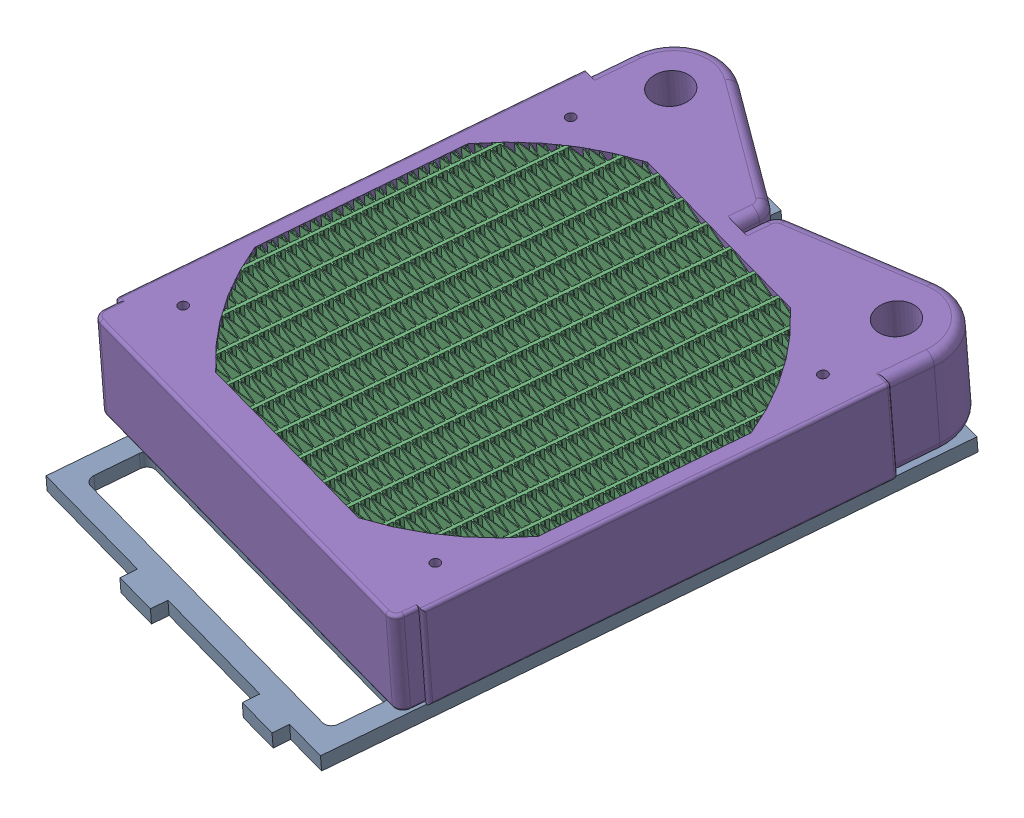
SolidWorks assembly Radiator Panel, configuration Default. Lengths in mm.
Overall size (161.44 74.04 205.59).
6 component instances, 3 part files, 12 mates.
Components (placement in the parent):
- Radiator Panel-1: Radiator Panel [Default] at (-37.0498 33.3786 -16.5806) x (-0.974635 0.090692 -0.204603) z (-0.214715 -0.121053 0.969146) size (114.3 4.76 187.33)
- MCR120-1: MCR120 [Default] at (-50.8395 45.9487 54.6789) x (0.974635 -0.090692 0.204603) z (-0.214715 -0.121053 0.969146) size (128 30.16 162)
- 0.25in Spacer-1: 0.25in Spacer [Default] at (2.846 22.262 45.0413) x (0.997996 -0.063126 -0.004364) z (-0.004364 -0.137455 0.990498) size (6.35 6.35 6.35)
- 0.25in Spacer-2: 0.25in Spacer [Default] at (-99.4907 31.7846 23.5579) x (0.997996 -0.063126 -0.004364) z (-0.004364 -0.137455 0.990498) size (6.35 6.35 6.35)
- 0.25in Spacer-3: 0.25in Spacer [Default] at (-76.9455 44.4952 -78.2024) x (0.997996 -0.063126 -0.004364) z (-0.004364 -0.137455 0.990498) size (6.35 6.35 6.35)
- 0.25in Spacer-4: 0.25in Spacer [Default] at (25.3911 34.9725 -56.719) x (0.997996 -0.063126 -0.004364) z (-0.004364 -0.137455 0.990498) size (6.35 6.35 6.35)
Mates (geometry in assembly coordinates):
- Concentric1: concentric aligned: circle of Radiator Panel-1; circle of MCR120-1
- Concentric2: concentric anti-aligned: circle of Radiator Panel-1; circle of MCR120-1
- Concentric3: concentric aligned: circle of Radiator Panel-1; circle of MCR120-1
- Concentric4: concentric aligned: circle of Radiator Panel-1; circle of 0.25in Spacer-1
- Coincident2: coincident anti-aligned: plane of Radiator Panel-1 through (-0.4376 17.4339 81.2696) normal (0.063126 0.988494 0.137455); plane of 0.25in Spacer-1 through (2.846 22.262 45.0413) normal (-0.063126 -0.988494 -0.137455)
- Concentric5: concentric aligned: circle of Radiator Panel-1; circle of 0.25in Spacer-2
- Coincident3: coincident anti-aligned: plane of Radiator Panel-1 through (-0.4376 17.4339 81.2696) normal (0.063126 0.988494 0.137455); plane of 0.25in Spacer-2 through (-99.4907 31.7846 23.5579) normal (-0.063126 -0.988494 -0.137455)
- Concentric6: concentric aligned: circle of Radiator Panel-1; circle of 0.25in Spacer-4
- Coincident4: coincident anti-aligned: plane of Radiator Panel-1 through (-0.4376 17.4339 81.2696) normal (0.063126 0.988494 0.137455); plane of 0.25in Spacer-4 through (25.3911 34.9725 -56.719) normal (-0.063126 -0.988494 -0.137455)
- Concentric7: concentric aligned: circle of Radiator Panel-1; circle of 0.25in Spacer-3
- Coincident5: coincident anti-aligned: plane of Radiator Panel-1 through (-0.4376 17.4339 81.2696) normal (0.063126 0.988494 0.137455); plane of 0.25in Spacer-3 through (-76.9455 44.4952 -78.2024) normal (-0.063126 -0.988494 -0.137455)
- Coincident6: coincident anti-aligned: plane of MCR120-1 through (-112.66 37.7729 32.7384) normal (-0.063126 -0.988494 -0.137455); plane of 0.25in Spacer-2 through (-99.0898 38.0615 24.4308) normal (0.063126 0.988494 0.137455)
